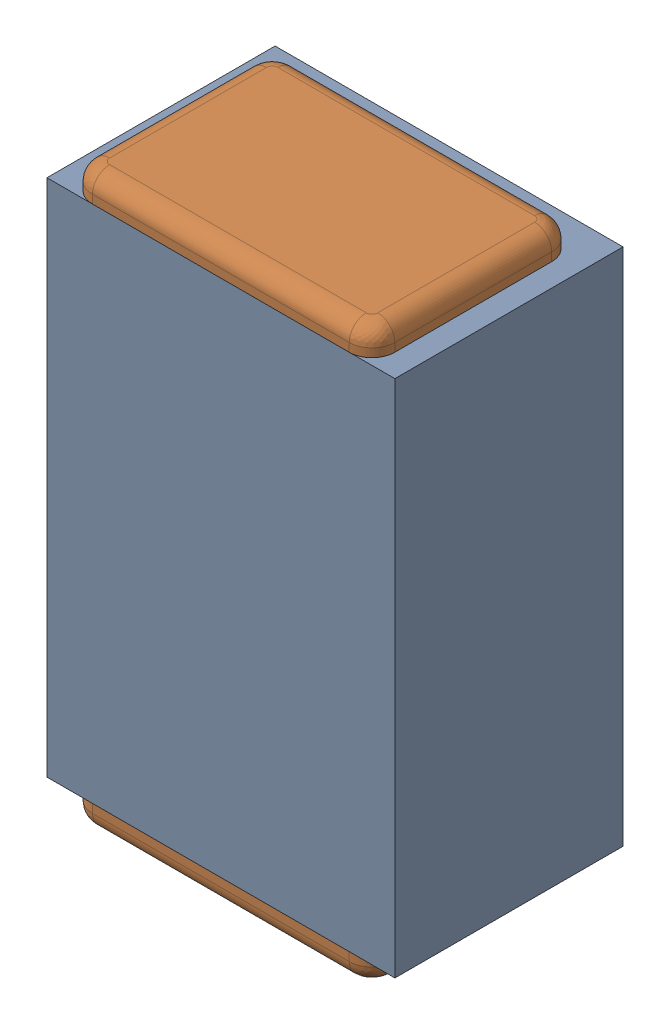
SolidWorks assembly C23, configuration Default. Lengths in mm.
Overall size (0.61 1 0.4).
3 component instances, 2 part files, 0 mates.
Components (placement in the parent):
- 1088881848-1: 1088881848 [Default] at (8.475 49.2 -2.044) size (0.61 0.91 0.4)
  - Extruded-1-1: Extruded-1 [Default] at origin size (0.61 0.91 0.4)
- C0402-1: C0402 [Default] at (8.4749 49.1999 -1.644) x (0 -1 0) z (1 0 0) size (1 0.36 0.54)
